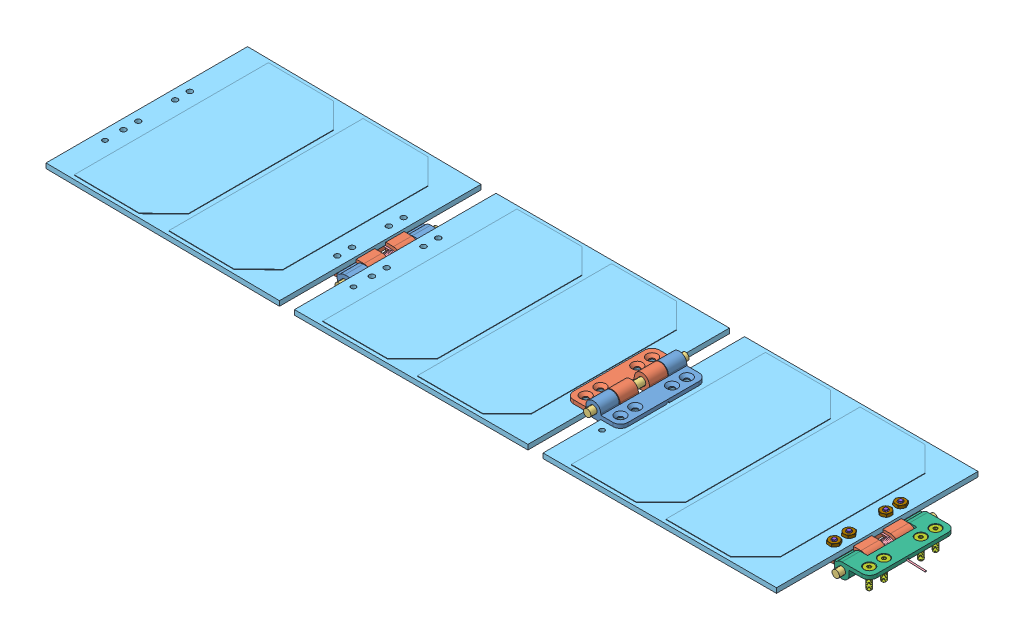
SolidWorks assembly Hinge_Assembly(deployed), configuration Default. Lengths in mm.
Overall size (319.45 14.54 82).
26 component instances, 9 part files, 52 mates.
Components (placement in the parent):
- H2-1: H2 [Default] at (18.5816 33.4244 26.846) size (14.1 6.1 35)
- H1-1: H1 [Default] at (18.5816 33.4244 54.096) x (-0.999939 0.011061 0) z (0 0 -1) size (14.2 6.2 35)
- PIN-1: PIN [Default] at (18.5816 33.4244 24.346) x (0.225287 0.974292 0) z (0 0 1) size (3 3 40)
- 9271K599_Torsion Spring-1: 9271K599_Torsion Spring [9271K599] at (18.6062 33.1334 42.5303) x (-0.008726 0.008727 0.999924) z (0.999962 0 0.008727) size (5.82 4.73 38.09)
- Solar_Panel_FULL-1: Solar_Panel_FULL [Default] at (69.1316 35.4744 44.346) x (1 0 0) z (0 1 0) size (95 82 2.2)
- Solar_Panel_FULL-2: Solar_Panel_FULL [Default] at (-31.992 36.084 44.346) x (0.999939 -0.011061 0) z (0.011061 0.999939 0) size (95 82 2.2)
- H1-2: H1 [Default] at (119.7316 39.5744 34.596) x (-1 0 0) z (0 0 1) size (14.2 6.2 35)
- H2-2: H2 [Default] at (119.7316 39.5744 61.846) x (1 0 0) z (0 0 -1) size (14.1 6.1 35)
- Solar_Panel_FULL-3: Solar_Panel_FULL [Default] at (170.2816 35.5244 44.346) x (1 0 0) z (0 1 0) size (95 82 2.2)
- H1-3: H1 [Default] at (220.8816 33.4244 54.096) x (-1 0 0) z (0 0 -1) size (14.2 6.2 35)
- PIN-2: PIN [Default] at (220.8816 33.4244 24.346) size (3 3 40)
- PIN-3: PIN [Default] at (119.7316 39.5744 24.346) size (3 3 40)
- H2_Chassis-1: H2_Chassis [Default] at (220.8816 33.4244 26.846) size (14.25 6 35)
- 92125A054_18-8 Stainless Steel Hex Drive Flat Head Screw-1: 92125A054_18-8 Stainless Steel Hex Drive Flat Head Screw [92125A054] at (228.0066 32.2844 36.846) x (1 0 0) z (0 1 0) size (4 4 8.23)
- 92125A054_18-8 Stainless Steel Hex Drive Flat Head Screw-2: 92125A054_18-8 Stainless Steel Hex Drive Flat Head Screw [92125A054] at (228.0066 32.2844 57.846) x (1 0 0) z (0 1 0) size (4 4 8.23)
- 92125A054_18-8 Stainless Steel Hex Drive Flat Head Screw-3: 92125A054_18-8 Stainless Steel Hex Drive Flat Head Screw [92125A054] at (228.0066 32.2844 51.846) x (1 0 0) z (0 1 0) size (4 4 8.23)
- 92125A054_18-8 Stainless Steel Hex Drive Flat Head Screw-4: 92125A054_18-8 Stainless Steel Hex Drive Flat Head Screw [92125A054] at (228.0066 32.2844 30.846) x (1 0 0) z (0 1 0) size (4 4 8.23)
- 92125A051_18-8 Stainless Steel Hex Drive Flat Head Screw-1: 92125A051_18-8 Stainless Steel Hex Drive Flat Head Screw [92125A051] at (213.7816 36.6644 36.846) x (1 0 0) z (0 -1 0) size (4 4 5.21)
- 92125A051_18-8 Stainless Steel Hex Drive Flat Head Screw-2: 92125A051_18-8 Stainless Steel Hex Drive Flat Head Screw [92125A051] at (213.7816 36.6644 51.846) x (1 0 0) z (0 -1 0) size (4 4 5.21)
- 92125A051_18-8 Stainless Steel Hex Drive Flat Head Screw-3: 92125A051_18-8 Stainless Steel Hex Drive Flat Head Screw [92125A051] at (213.7816 36.6644 30.846) x (1 0 0) z (0 -1 0) size (4 4 5.21)
- 92125A051_18-8 Stainless Steel Hex Drive Flat Head Screw-4: 92125A051_18-8 Stainless Steel Hex Drive Flat Head Screw [92125A051] at (213.7816 36.6644 57.846) x (1 0 0) z (0 -1 0) size (4 4 5.21)
- M2 Thin_90710A020_18-8 Stainless Steel Thin Hex Nut-1: M2 Thin_90710A020_18-8 Stainless Steel Thin Hex Nut [90710A020] at (213.7816 38.1244 36.846) x (0.988814 0 0.149152) z (-0.149152 0 0.988814) size (4 1.51 4.62)
- M2 Thin_90710A020_18-8 Stainless Steel Thin Hex Nut-2: M2 Thin_90710A020_18-8 Stainless Steel Thin Hex Nut [90710A020] at (213.7816 38.1244 51.846) x (0.935029 0 0.354571) z (-0.354571 0 0.935029) size (4 1.51 4.62)
- M2 Thin_90710A020_18-8 Stainless Steel Thin Hex Nut-3: M2 Thin_90710A020_18-8 Stainless Steel Thin Hex Nut [90710A020] at (213.7816 38.1244 57.846) x (-0.837169 0 -0.546944) z (-0.546944 0 0.837169) size (4 1.51 4.62)
- M2 Thin_90710A020_18-8 Stainless Steel Thin Hex Nut-4: M2 Thin_90710A020_18-8 Stainless Steel Thin Hex Nut [90710A020] at (213.7816 38.1244 30.846) x (-0.837169 0 -0.546944) z (-0.546944 0 0.837169) size (4 1.51 4.62)
- 9271K599_Torsion Spring-2: 9271K599_Torsion Spring [9271K599] at (220.8861 33.1618 46.1681) x (-0.008726 0.000076 -0.999962) z (-0.999924 0.008726 0.008727) size (5.82 4.73 38.09)
Mates (geometry in assembly coordinates):
- Concentric1: concentric anti-aligned: cylinder of H2-1 through (18.5816 33.4244 61.846) axis (0 0 -1) radius 1.55; cylinder of H1-1 through (18.5816 33.4244 46.596) axis (0 0 1) radius 1.6
- Distance1: distance = 0.25 mm anti-aligned: plane of H2-1 through (18.5816 33.4244 34.346) normal (0 0 1); plane of H1-1 through (18.5816 33.4244 34.596) normal (0 0 -1)
- Concentric2: concentric anti-aligned: cylinder of H1-1 through (18.5816 33.4244 34.596) axis (0 0 1) radius 1.6; cylinder of PIN-1 through (18.5816 33.4244 64.346) axis (0 0 -1) radius 1.5
- Distance2: distance = 2.5 mm aligned: plane of PIN-1 through (18.5816 33.4244 64.346) normal (0 0 1); plane of H2-1 through (18.5816 33.4244 61.846) normal (0 0 1)
- Coincident1: coincident anti-aligned: plane of H2-1 through (21.6316 35.4744 34.346) normal (0 1 0); plane of Solar_Panel_FULL-1 through (69.1316 35.4744 44.346) normal (0 -1 0)
- Concentric3: concentric anti-aligned: circle of H2-1; circle of Solar_Panel_FULL-1
- Parallel1: parallel aligned: line of H2-1 through (29.6316 33.9744 58.846) axis (0 0 -1); line of Solar_Panel_FULL-1 through (21.6316 37.4744 85.346) axis (0 0 -1)
- Coincident4: coincident anti-aligned: plane of H1-1 through (15.505 35.5586 46.596) normal (0.011061 0.999939 0); plane of Solar_Panel_FULL-2 through (-31.992 36.084 44.346) normal (-0.011061 -0.999939 0)
- Concentric4: concentric anti-aligned: circle of H1-1; circle of Solar_Panel_FULL-2
- Parallel2: parallel anti-aligned: line of H1-1 through (7.4889 34.1472 29.846) axis (0 0 1); line of Solar_Panel_FULL-2 through (15.5272 37.5584 85.346) axis (0 0 -1)
- Concentric6: concentric anti-aligned: circle of Solar_Panel_FULL-1; circle of 90695A033_Steel Thin Hex Nut-1
- Coincident8: coincident anti-aligned: plane of Solar_Panel_FULL-1 through (69.1316 37.4744 44.346) normal (0 1 0); plane of H1-2 through (116.6316 37.4744 42.096) normal (0 -1 0)
- Parallel3: parallel aligned: line of Solar_Panel_FULL-1 through (116.6316 37.4744 85.346) axis (0 0 -1); line of H1-2 through (108.6316 38.9744 58.846) axis (0 0 -1)
- Concentric7: concentric anti-aligned: cylinder of H1-2 through (119.7316 39.5744 54.096) axis (0 0 -1) radius 1.6; cylinder of H2-2 through (119.7316 39.5744 54.346) axis (0 0 1) radius 1.55
- Distance3: distance = 0.25 mm anti-aligned: plane of H1-2 through (119.7316 39.5744 54.096) normal (0 0 1); plane of H2-2 through (119.7316 39.5744 54.346) normal (0 0 -1)
- Coincident12: coincident anti-aligned: plane of H2-2 through (122.7816 37.5244 54.346) normal (0 -1 0); plane of Solar_Panel_FULL-3 through (170.2816 37.5244 44.346) normal (0 1 0)
- Concentric8: concentric aligned: circle of H2-2; circle of Solar_Panel_FULL-3
- Parallel4: parallel anti-aligned: line of H2-2 through (130.7816 39.0244 29.846) axis (0 0 1); line of Solar_Panel_FULL-3 through (122.7816 37.5244 85.346) axis (0 0 -1)
- Coincident13: coincident anti-aligned: plane of Solar_Panel_FULL-3 through (170.2816 35.5244 44.346) normal (0 -1 0); plane of H1-3 through (217.7816 35.5244 46.596) normal (0 1 0)
- Concentric9: concentric anti-aligned: circle of Solar_Panel_FULL-3; circle of H1-3
- Coincident15: coincident anti-aligned: line of Solar_Panel_FULL-3 through (217.7816 35.5244 85.346) axis (0 0 -1); line of H1-3 through (217.7816 35.5244 26.846) axis (0 0 1)
- Concentric10: concentric anti-aligned: cylinder of H1-3 through (220.8816 33.4244 34.596) axis (0 0 1) radius 1.6; cylinder of H2-3 through (220.5816 33.4244 61.846) axis (0 0 -1) radius 1.5
- Distance4: distance = 0.25 mm anti-aligned: plane of H1-3 through (220.8816 33.4244 34.596) normal (0 0 -1); plane of H2-3 through (220.5816 33.4244 34.346) normal (0 0 1)
- Concentric11: concentric aligned: cylinder of H2-3 through (220.5816 33.4244 34.346) axis (0 0 -1) radius 1.5; cylinder of PIN-2 through (220.8816 33.4244 64.346) axis (0 0 -1) radius 1.5
- Distance5: distance = 2.5 mm aligned: plane of H2-3 through (220.5816 33.4244 26.846) normal (0 0 -1); plane of PIN-2 through (220.8816 33.4244 24.346) normal (0 0 -1)
- Parallel7: parallel anti-aligned: line of H1-3 through (217.7816 34.0244 26.846) axis (-1 0 0); line of H2-3 through (223.5816 33.6744 26.846) axis (1 0 0)
- Parallel9: parallel aligned: line of Solar_Panel_FULL-1 through (21.6316 37.4744 3.346) axis (1 0 0); line of Solar_Panel_FULL-3 through (122.7816 37.5244 3.346) axis (1 0 0)
- Coincident16: coincident anti-aligned: cylinder of Solar_Panel_FULL-1 through (112.6316 37.4744 57.846) axis (0 -1 0) radius 1.1; circle of H1-2
- Concentric12: concentric anti-aligned: cylinder of H2-2 through (119.7316 39.5744 26.846) axis (0 0 1) radius 1.55; cylinder of PIN-3 through (119.7316 39.5744 64.346) axis (0 0 -1) radius 1.5
- Distance6: distance = 2.5 mm aligned: plane of PIN-3 through (119.7316 39.5744 24.346) normal (0 0 -1); plane of H2-2 through (119.7316 39.5744 26.846) normal (0 0 -1)
- Concentric13: concentric aligned: cylinder of PIN-2 through (220.8816 33.4244 64.346) axis (0 0 -1) radius 1.5; cylinder of H2_Chassis-1 through (220.8816 33.4244 34.346) axis (0 0 -1) radius 1.5
- Concentric14: concentric anti-aligned: cylinder of H1-3 through (220.8816 33.4244 46.596) axis (0 0 1) radius 1.6; cylinder of PIN-2 through (220.8816 33.4244 64.346) axis (0 0 -1) radius 1.5
- Distance7: distance = 0.25 mm anti-aligned: plane of H1-3 through (220.8816 33.4244 34.596) normal (0 0 -1); plane of H2_Chassis-1 through (220.8816 33.4244 34.346) normal (0 0 1)
- Distance8: distance = 2.5 mm aligned: plane of PIN-2 through (220.8816 33.4244 24.346) normal (0 0 -1); plane of H2_Chassis-1 through (220.8816 33.4244 26.846) normal (0 0 -1)
- Coincident17: coincident aligned: cone of H2_Chassis-1 through (228.0066 36.4244 36.846) axis (0 -1 0); cone of 92125A054_18-8 Stainless Steel Hex Drive Flat Head Screw-1 through (228.0066 36.2244 36.846) axis (0 -1 0)
- Coincident18: coincident aligned: cone of H2_Chassis-1 through (228.0066 36.4244 30.846) axis (0 -1 0); cone of 92125A054_18-8 Stainless Steel Hex Drive Flat Head Screw-4 through (228.0066 36.2244 30.846) axis (0 -1 0)
- Coincident19: coincident aligned: cone of H2_Chassis-1 through (228.0066 36.4244 51.846) axis (0 -1 0); cone of 92125A054_18-8 Stainless Steel Hex Drive Flat Head Screw-3 through (228.0066 36.2244 51.846) axis (0 -1 0)
- Coincident20: coincident aligned: cone of H2_Chassis-1 through (228.0066 36.4244 57.846) axis (0 -1 0); cone of 92125A054_18-8 Stainless Steel Hex Drive Flat Head Screw-2 through (228.0066 36.2244 57.846) axis (0 -1 0)
- Coincident22: coincident aligned: cone of H1-3 through (213.7816 35.1244 57.846) axis (0 1 0); cone of 92125A051_18-8 Stainless Steel Hex Drive Flat Head Screw-4 through (213.7816 34.2244 57.846) axis (0 1 0)
- Coincident23: coincident aligned: cone of H1-3 through (213.7816 35.1244 51.846) axis (0 1 0); cone of 92125A051_18-8 Stainless Steel Hex Drive Flat Head Screw-2 through (213.7816 34.2244 51.846) axis (0 1 0)
- Coincident24: coincident aligned: cone of H1-3 through (213.7816 35.1244 36.846) axis (0 1 0); cone of 92125A051_18-8 Stainless Steel Hex Drive Flat Head Screw-1 through (213.7816 34.2244 36.846) axis (0 1 0)
- Coincident25: coincident aligned: cone of H1-3 through (213.7816 35.1244 30.846) axis (0 1 0); cone of 92125A051_18-8 Stainless Steel Hex Drive Flat Head Screw-3 through (213.7816 34.2244 30.846) axis (0 1 0)
- Concentric18: concentric: circle of Solar_Panel_FULL-3; circle of 90695A033_Steel Thin Hex Nut-2
- Coincident27: coincident anti-aligned: plane of Solar_Panel_FULL-3 through (170.2816 37.5244 44.346) normal (0 1 0); plane of 90695A033_Steel Thin Hex Nut-2 through (213.7816 37.9344 30.846) normal (0 -1 0)
- Concentric19: concentric aligned: circle of Solar_Panel_FULL-3; circle of M2 Thin_90710A020_18-8 Stainless Steel Thin Hex Nut-1
- Coincident28: coincident anti-aligned: plane of Solar_Panel_FULL-3 through (170.2816 37.5244 44.346) normal (0 1 0); plane of M2 Thin_90710A020_18-8 Stainless Steel Thin Hex Nut-1 through (211.9762 37.5244 35.406) normal (0 -1 0)
- Concentric20: concentric aligned: circle of Solar_Panel_FULL-3; circle of M2 Thin_90710A020_18-8 Stainless Steel Thin Hex Nut-2
- Coincident29: coincident anti-aligned: plane of Solar_Panel_FULL-3 through (170.2816 37.5244 44.346) normal (0 1 0); plane of M2 Thin_90710A020_18-8 Stainless Steel Thin Hex Nut-2 through (212.321 37.5244 50.0572) normal (0 -1 0)
- Coincident30: coincident anti-aligned: plane of Solar_Panel_FULL-3 through (170.2816 37.5244 44.346) normal (0 1 0); plane of M2 Thin_90710A020_18-8 Stainless Steel Thin Hex Nut-4 through (216.0875 37.5244 30.9733) normal (0 -1 0)
- Concentric21: concentric anti-aligned: circle of Solar_Panel_FULL-3; circle of M2 Thin_90710A020_18-8 Stainless Steel Thin Hex Nut-4
- Coincident31: coincident anti-aligned: plane of Solar_Panel_FULL-3 through (170.2816 37.5244 44.346) normal (0 1 0); plane of M2 Thin_90710A020_18-8 Stainless Steel Thin Hex Nut-3 through (216.0875 37.5244 57.9733) normal (0 -1 0)
- Concentric22: concentric anti-aligned: circle of Solar_Panel_FULL-3; circle of M2 Thin_90710A020_18-8 Stainless Steel Thin Hex Nut-3
